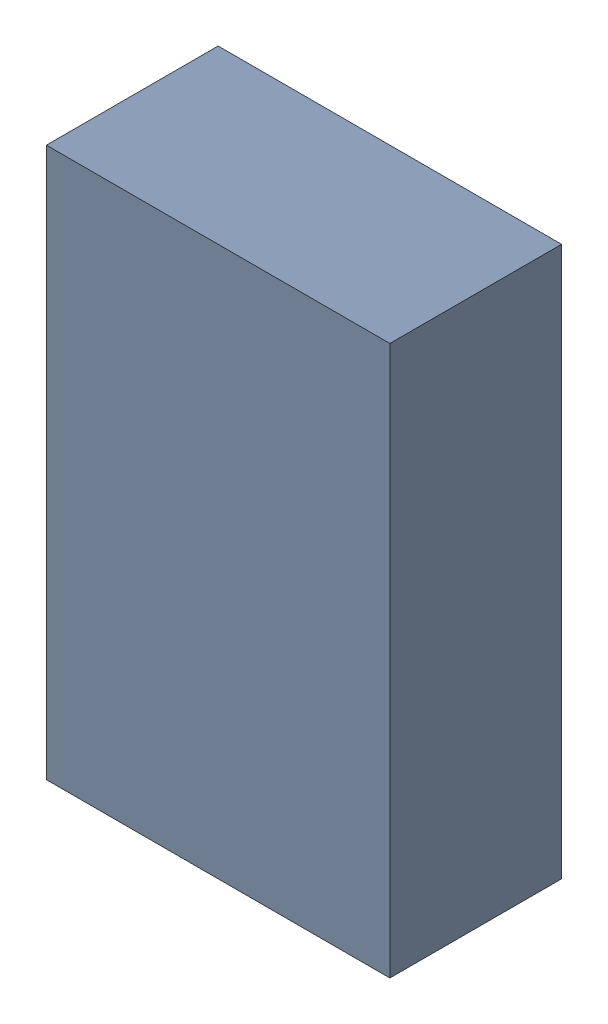
SolidWorks assembly C2, configuration Default. Lengths in mm.
Overall size (1.27 2.03 0.64).
2 component instances, 1 part files, 0 mates.
Components (placement in the parent):
- 948816432-1: 948816432 [Default] at (26.8464 8.18 0) size (1.27 2.03 0.64)
  - Extruded_7-1: Extruded_7 [Default] at origin size (1.27 2.03 0.64)
